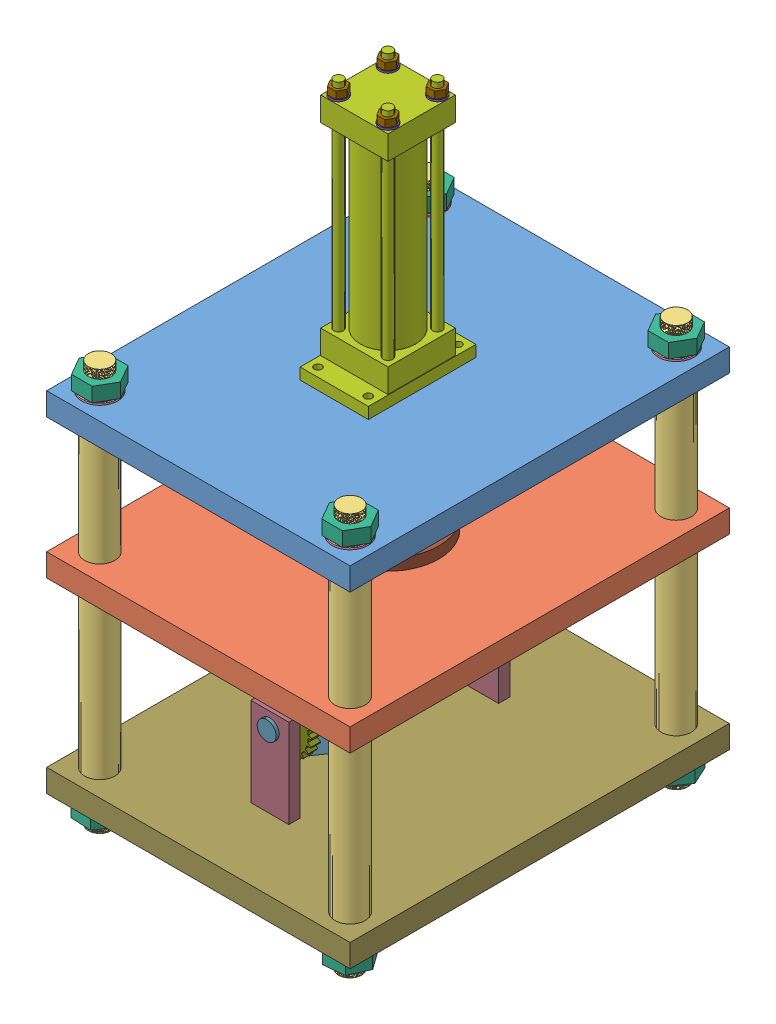
SolidWorks assembly Ensamblaje 1 placas, configuration Predeterminado. Lengths in mm.
Overall size (508 1049.7 635).
49 component instances, 16 part files, 76 mates.
Components (placement in the parent):
- placa 1-1: placa 1 [Predeterminado] at (113.4561 256.4005 589.4712) size (508 38.1 635)
- placa 2-1: placa 2 [Predeterminado] at (113.4561 22.9179 589.4712) size (508 38.1 635)
- Tarrox-1: Tarrox [Predeterminado] at (323.0061 -334.1495 862.5212) x (0.933111 0 -0.359587) z (0.359587 0 0.933111) size (50.8 673.1 50.8)
- Tarrox-2: Tarrox [Predeterminado] at (323.0061 -334.1495 316.4212) x (0.79348 0 -0.608597) z (0.608597 0 0.79348) size (50.8 673.1 50.8)
- Tarrox-3: Tarrox [Predeterminado] at (-96.0939 -334.1495 862.5212) size (50.8 673.1 50.8)
- Tarrox-4: Tarrox [Predeterminado] at (-96.0939 -334.1495 316.4212) size (50.8 673.1 50.8)
- rondana plana de 1.5in-1: rondana plana de 1.5in [Predeterminado] at (-96.0939 294.5005 862.5212) x (0.930502 0 0.366288) z (-0.366288 0 0.930502) size (60 3 60)
- rondana plana de 1.5in-2: rondana plana de 1.5in [Predeterminado] at (323.0061 294.5005 862.5212) x (0.967524 0 0.252778) z (-0.252778 0 0.967524) size (60 3 60)
- rondana plana de 1.5in-3: rondana plana de 1.5in [Predeterminado] at (323.0061 294.5005 316.4212) size (60 3 60)
- rondana plana de 1.5in-4: rondana plana de 1.5in [Predeterminado] at (-96.0939 294.5005 316.4212) x (-0.006863 0 -0.999976) z (0.999976 0 -0.006863) size (60 3 60)
- rondana plana de 1.5in-5: rondana plana de 1.5in [Predeterminado] at (-96.0939 -292.6995 862.5212) x (0.88029 0 -0.474437) z (0.474437 0 0.88029) size (60 3 60)
- rondana plana de 1.5in-6: rondana plana de 1.5in [Predeterminado] at (323.0061 -292.6995 862.5212) x (0.975439 0 0.220268) z (-0.220268 0 0.975439) size (60 3 60)
- rondana plana de 1.5in-7: rondana plana de 1.5in [Predeterminado] at (323.0061 -292.6995 316.4212) size (60 3 60)
- rondana plana de 1.5in-8: rondana plana de 1.5in [Predeterminado] at (-96.0939 -292.6995 316.4212) size (60 3 60)
- rondana de presión-1: rondana de presión [Predeterminado] at (323.0061 297.5005 862.5212) size (55 3 54.98)
- rondana de presión-2: rondana de presión [Predeterminado] at (-96.0939 297.5005 862.5212) size (55 3 54.98)
- rondana de presión-3: rondana de presión [Predeterminado] at (323.0061 297.5005 316.4212) size (55 3 54.98)
- rondana de presión-4: rondana de presión [Predeterminado] at (-96.0939 297.5005 316.4212) size (55 3 54.98)
- rondana de presión-5: rondana de presión [Predeterminado] at (-96.0939 -295.6995 862.5212) x (0.998826 0 0.048446) z (-0.048446 0 0.998826) size (55 3 54.98)
- rondana de presión-6: rondana de presión [Predeterminado] at (-96.0939 -295.6995 316.4212) x (0.996973 0 -0.077754) z (0.077754 0 0.996973) size (55 3 54.98)
- rondana de presión-7: rondana de presión [Predeterminado] at (323.0061 -295.6995 316.4212) size (55 3 54.98)
- rondana de presión-8: rondana de presión [Predeterminado] at (323.0061 -295.6995 862.5212) size (55 3 54.98)
- tuerca de 1.5in-1: tuerca de 1.5in [Predeterminado] at (323.0061 300.5005 862.5212) size (69.28 24 60)
- tuerca de 1.5in-2: tuerca de 1.5in [Predeterminado] at (-96.0939 300.5005 862.5212) size (69.28 24 60)
- tuerca de 1.5in-3: tuerca de 1.5in [Predeterminado] at (323.0061 300.5005 316.4212) size (69.28 24 60)
- tuerca de 1.5in-4: tuerca de 1.5in [Predeterminado] at (-96.0939 300.5005 316.4212) size (69.28 24 60)
- tuerca de 1.5in-5: tuerca de 1.5in [Predeterminado] at (323.0061 -319.6995 862.5212) x (-0.995095 0 0.098924) z (-0.098924 0 -0.995095) size (69.28 24 60)
- tuerca de 1.5in-6: tuerca de 1.5in [Predeterminado] at (323.0061 -319.6995 316.4212) x (-0.995824 0 -0.091299) z (0.091299 0 -0.995824) size (69.28 24 60)
- tuerca de 1.5in-7: tuerca de 1.5in [Predeterminado] at (-96.0939 -319.6995 316.4212) x (-0.401422 0 -0.915893) z (0.915893 0 -0.401422) size (69.28 24 60)
- tuerca de 1.5in-8: tuerca de 1.5in [Predeterminado] at (-96.0939 -319.6995 862.5212) x (-0.998486 0 -0.055002) z (0.055002 0 -0.998486) size (69.28 24 60)
- Ensamblaje piston-1: Ensamblaje piston [Predeterminado] at (194.8258 497.708 168.4212) size (114.3 421.05 180)
  - base de piston-1: base de piston [Predeterminado] at (-81.3698 -203.2076 421.05) size (114.3 421.05 180)
  - rondana de 16mm-1: rondana de 16mm [Predeterminado] at (-122.726 193.8424 462.4062) size (28 3 28)
  - rondana de 16mm-2: rondana de 16mm [Predeterminado] at (-122.726 193.8424 379.6938) size (28 3 28)
  - rondana de 16mm-3: rondana de 16mm [Predeterminado] at (-40.0135 193.8424 462.4062) x (0.999451 0 0.033137) z (-0.033137 0 0.999451) size (28 3 28)
  - rondana de 16mm-4: rondana de 16mm [Predeterminado] at (-40.0135 193.8424 379.6938) size (28 3 28)
  - tuerca de 16mm-1: tuerca de 16mm [Predeterminado] at (-40.0135 196.8424 462.4062) size (27.71 12 24.32)
  - tuerca de 16mm-2: tuerca de 16mm [Predeterminado] at (-40.0135 196.8424 379.6938) size (27.71 12 24.32)
  - tuerca de 16mm-3: tuerca de 16mm [Predeterminado] at (-122.726 196.8424 462.4062) size (27.71 12 24.32)
  - tuerca de 16mm-4: tuerca de 16mm [Predeterminado] at (-122.726 196.8424 379.6938) size (27.71 12 24.32)
- bastago 1-1: bastago 1 [Predeterminado] at (113.4561 101.0679 589.4712) x (0.034652 0 0.999399) z (-0.999399 0 0.034652) size (45 254 45)
- brida-1: brida [Predeterminado] at (113.4561 61.0179 589.4712) size (170 40.05 170)
- placa 3-1: placa 3 [Predeterminado] at (113.4561 -289.6995 589.4712) size (508 38.1 635)
- base de mamelon 1-1: base de mamelon 1 [Predeterminado] at (81.7061 -251.5995 768.2712) size (63.5 148.55 19.05)
- base de mamelon 1-2: base de mamelon 1 [Predeterminado] at (81.7061 -251.5995 417.0212) size (63.5 148.55 19.05)
- Ensamblaje 10-2: Ensamblaje 10 [Predeterminado] at (114.3023 -116.2053 284.6712) x (-0.012069 0.999927 0) z (0 0 1) size (127 160.79 381)
  - exagono 1-1: exagono 1 [Predeterminado] at (-12.2332 0.9939 457.2) size (127 109.99 381)
  - base 10-1: base 10 [Predeterminado] at (-43.9832 55.9866 431.8) size (63.5 50.8 254)
  - engrane 1-1: engrane 1 [Predeterminado] at (-12.2332 0.9939 466.725) x (0.999934 -0.011529 0) z (0 0 1) size (101.2 101.2 15.88)
Mates (geometry in assembly coordinates):
- Coincidente5: coincident aligned: plane of placa 1-1 through (-140.5439 294.5005 906.9712) normal (0 0 1); plane of placa 2-1 through (-140.5439 61.0179 906.9712) normal (0 0 1)
- Coincidente6: coincident aligned: plane of placa 1-1 through (367.4561 294.5005 906.9712) normal (1 0 0); plane of placa 2-1 through (367.4561 61.0179 906.9712) normal (1 0 0)
- Concéntrica1: concentric aligned: cylinder of placa 1-1 through (323.0061 202.5189 862.5212) axis (0 1 0) radius 19.05; cylinder of Tarrox-1 through (323.0061 256.4005 862.5212) axis (0 1 0) radius 19.05
- Coincidente7: coincident anti-aligned: plane of placa 1-1 through (113.4561 256.4005 589.4712) normal (0 -1 0); plane of Tarrox-1 through (323.0061 256.4005 862.5212) normal (0 1 0)
- Concéntrica2: concentric aligned: cylinder of placa 1-1 through (323.0061 202.5189 316.4212) axis (0 1 0) radius 19.05; cylinder of Tarrox-2 through (323.0061 256.4005 316.4212) axis (0 1 0) radius 19.05
- Coincidente8: coincident anti-aligned: plane of placa 1-1 through (113.4561 256.4005 589.4712) normal (0 -1 0); plane of Tarrox-2 through (323.0061 256.4005 316.4212) normal (0 1 0)
- Concéntrica3: concentric aligned: cylinder of placa 1-1 through (-96.0939 202.5189 862.5212) axis (0 1 0) radius 19.05; cylinder of Tarrox-3 through (-96.0939 256.4005 862.5212) axis (0 1 0) radius 19.05
- Coincidente9: coincident anti-aligned: plane of placa 1-1 through (113.4561 256.4005 589.4712) normal (0 -1 0); plane of Tarrox-3 through (-96.0939 256.4005 862.5212) normal (0 1 0)
- Concéntrica4: concentric aligned: cylinder of placa 1-1 through (-96.0939 202.5189 316.4212) axis (0 1 0) radius 19.05; cylinder of Tarrox-4 through (-96.0939 256.4005 316.4212) axis (0 1 0) radius 19.05
- Coincidente10: coincident anti-aligned: plane of placa 1-1 through (113.4561 256.4005 589.4712) normal (0 -1 0); plane of Tarrox-4 through (-96.0939 256.4005 316.4212) normal (0 1 0)
- Concéntrica5: concentric aligned: cylinder of Tarrox-3 through (-96.0939 338.9505 862.5212) axis (0 -1 0) radius 25.4; cylinder of rondana plana de 1.5in-1 through (-96.0939 297.5005 862.5212) axis (0 -1 0) radius 19.05
- Coincidente11: coincident anti-aligned: plane of placa 1-1 through (113.4561 294.5005 589.4712) normal (0 1 0); plane of rondana plana de 1.5in-1 through (-96.0939 294.5005 862.5212) normal (0 -1 0)
- Concéntrica6: concentric aligned: cylinder of Tarrox-1 through (323.0061 338.9505 862.5212) axis (0 -1 0) radius 25.4; cylinder of rondana plana de 1.5in-2 through (323.0061 297.5005 862.5212) axis (0 -1 0) radius 19.05
- Coincidente12: coincident anti-aligned: plane of placa 1-1 through (113.4561 294.5005 589.4712) normal (0 1 0); plane of rondana plana de 1.5in-2 through (323.0061 294.5005 862.5212) normal (0 -1 0)
- Concéntrica7: concentric aligned: cylinder of Tarrox-2 through (323.0061 338.9505 316.4212) axis (0 -1 0) radius 25.4; cylinder of rondana plana de 1.5in-3 through (323.0061 297.5005 316.4212) axis (0 -1 0) radius 19.05
- Coincidente13: coincident anti-aligned: plane of placa 1-1 through (113.4561 294.5005 589.4712) normal (0 1 0); plane of rondana plana de 1.5in-3 through (323.0061 294.5005 316.4212) normal (0 -1 0)
- Concéntrica8: concentric aligned: cylinder of Tarrox-4 through (-96.0939 338.9505 316.4212) axis (0 -1 0) radius 25.4; cylinder of rondana plana de 1.5in-4 through (-96.0939 297.5005 316.4212) axis (0 -1 0) radius 19.05
- Coincidente14: coincident anti-aligned: plane of placa 1-1 through (113.4561 294.5005 589.4712) normal (0 1 0); plane of rondana plana de 1.5in-4 through (-96.0939 294.5005 316.4212) normal (0 -1 0)
- Concéntrica9: concentric aligned: cylinder of Tarrox-3 through (-96.0939 338.9505 862.5212) axis (0 -1 0) radius 25.4; cylinder of rondana plana de 1.5in-5 through (-96.0939 -289.6995 862.5212) axis (0 -1 0) radius 19.05
- Concéntrica10: concentric aligned: cylinder of Tarrox-1 through (323.0061 338.9505 862.5212) axis (0 -1 0) radius 25.4; cylinder of rondana plana de 1.5in-6 through (323.0061 -289.6995 862.5212) axis (0 -1 0) radius 19.05
- Concéntrica11: concentric aligned: cylinder of Tarrox-2 through (323.0061 338.9505 316.4212) axis (0 -1 0) radius 25.4; cylinder of rondana plana de 1.5in-7 through (323.0061 -289.6995 316.4212) axis (0 -1 0) radius 19.05
- Concéntrica12: concentric aligned: cylinder of Tarrox-4 through (-96.0939 338.9505 316.4212) axis (0 -1 0) radius 25.4; cylinder of rondana plana de 1.5in-8 through (-96.0939 -289.6995 316.4212) axis (0 -1 0) radius 19.05
- Concéntrica13: concentric aligned: cylinder of Tarrox-1 through (323.0061 338.9505 862.5212) axis (0 -1 0) radius 25.4; cylinder of rondana de presión-1 through (323.0061 300.5005 862.5212) axis (0 -1 0) radius 19.05
- Coincidente19: coincident anti-aligned: plane of rondana plana de 1.5in-2 through (323.0061 297.5005 862.5212) normal (0 1 0); plane of rondana de presión-1 through (323.0061 297.5005 862.5212) normal (0 -1 0)
- Concéntrica14: concentric aligned: cylinder of Tarrox-3 through (-96.0939 338.9505 862.5212) axis (0 -1 0) radius 25.4; cylinder of rondana de presión-2 through (-96.0939 300.5005 862.5212) axis (0 -1 0) radius 19.05
- Coincidente20: coincident anti-aligned: plane of rondana plana de 1.5in-1 through (-96.0939 297.5005 862.5212) normal (0 1 0); plane of rondana de presión-2 through (-96.0939 297.5005 862.5212) normal (0 -1 0)
- Concéntrica15: concentric aligned: cylinder of Tarrox-2 through (323.0061 338.9505 316.4212) axis (0 -1 0) radius 25.4; cylinder of rondana de presión-3 through (323.0061 300.5005 316.4212) axis (0 -1 0) radius 19.05
- Coincidente21: coincident anti-aligned: plane of rondana plana de 1.5in-3 through (323.0061 297.5005 316.4212) normal (0 1 0); plane of rondana de presión-3 through (323.0061 297.5005 316.4212) normal (0 -1 0)
- Concéntrica16: concentric aligned: cylinder of Tarrox-4 through (-96.0939 338.9505 316.4212) axis (0 -1 0) radius 25.4; cylinder of rondana de presión-4 through (-96.0939 300.5005 316.4212) axis (0 -1 0) radius 19.05
- Coincidente22: coincident anti-aligned: plane of rondana plana de 1.5in-4 through (-96.0939 297.5005 316.4212) normal (0 1 0); plane of rondana de presión-4 through (-96.0939 297.5005 316.4212) normal (0 -1 0)
- Concéntrica17: concentric aligned: cylinder of Tarrox-3 through (-96.0939 338.9505 862.5212) axis (0 -1 0) radius 25.4; cylinder of rondana de presión-5 through (-96.0939 -292.6995 862.5212) axis (0 -1 0) radius 19.05
- Coincidente23: coincident anti-aligned: plane of rondana plana de 1.5in-5 through (-96.0939 -292.6995 862.5212) normal (0 -1 0); plane of rondana de presión-5 through (-96.0939 -292.6995 862.5212) normal (0 1 0)
- Concéntrica18: concentric aligned: cylinder of Tarrox-4 through (-96.0939 338.9505 316.4212) axis (0 -1 0) radius 25.4; cylinder of rondana de presión-6 through (-96.0939 -292.6995 316.4212) axis (0 -1 0) radius 19.05
- Coincidente24: coincident anti-aligned: plane of rondana plana de 1.5in-8 through (-96.0939 -292.6995 316.4212) normal (0 -1 0); plane of rondana de presión-6 through (-96.0939 -292.6995 316.4212) normal (0 1 0)
- Coincidente25: coincident anti-aligned: plane of rondana plana de 1.5in-7 through (323.0061 -292.6995 316.4212) normal (0 -1 0); plane of rondana de presión-7 through (323.0061 -292.6995 316.4212) normal (0 1 0)
- Concéntrica19: concentric aligned: cylinder of Tarrox-2 through (323.0061 338.9505 316.4212) axis (0 -1 0) radius 25.4; cylinder of rondana de presión-7 through (323.0061 -292.6995 316.4212) axis (0 -1 0) radius 19.05
- Coincidente26: coincident anti-aligned: plane of rondana plana de 1.5in-6 through (323.0061 -292.6995 862.5212) normal (0 -1 0); plane of rondana de presión-8 through (323.0061 -292.6995 862.5212) normal (0 1 0)
- Concéntrica20: concentric aligned: cylinder of Tarrox-1 through (323.0061 338.9505 862.5212) axis (0 -1 0) radius 25.4; cylinder of rondana de presión-8 through (323.0061 -292.6995 862.5212) axis (0 -1 0) radius 19.05
- Concéntrica21: concentric aligned: cylinder of Tarrox-1 through (323.0061 338.9505 862.5212) axis (0 -1 0) radius 25.4; cylinder of tuerca de 1.5in-1 through (323.0061 324.5005 862.5212) axis (0 -1 0) radius 19.05
- Coincidente27: coincident anti-aligned: plane of rondana de presión-1 through (323.0061 300.5005 862.5212) normal (0 1 0); plane of tuerca de 1.5in-1 through (323.0061 300.5005 862.5212) normal (0 -1 0)
- Concéntrica22: concentric aligned: cylinder of Tarrox-3 through (-96.0939 338.9505 862.5212) axis (0 -1 0) radius 25.4; cylinder of tuerca de 1.5in-2 through (-96.0939 324.5005 862.5212) axis (0 -1 0) radius 19.05
- Coincidente28: coincident anti-aligned: plane of rondana de presión-2 through (-96.0939 300.5005 862.5212) normal (0 1 0); plane of tuerca de 1.5in-2 through (-96.0939 300.5005 862.5212) normal (0 -1 0)
- Concéntrica23: concentric aligned: cylinder of Tarrox-2 through (323.0061 338.9505 316.4212) axis (0 -1 0) radius 25.4; cylinder of tuerca de 1.5in-3 through (323.0061 324.5005 316.4212) axis (0 -1 0) radius 19.05
- Coincidente29: coincident anti-aligned: plane of rondana de presión-3 through (323.0061 300.5005 316.4212) normal (0 1 0); plane of tuerca de 1.5in-3 through (323.0061 300.5005 316.4212) normal (0 -1 0)
- Coincidente30: coincident anti-aligned: plane of rondana de presión-4 through (-96.0939 300.5005 316.4212) normal (0 1 0); plane of tuerca de 1.5in-4 through (-96.0939 300.5005 316.4212) normal (0 -1 0)
- Concéntrica24: concentric aligned: cylinder of Tarrox-4 through (-96.0939 338.9505 316.4212) axis (0 -1 0) radius 25.4; cylinder of tuerca de 1.5in-4 through (-96.0939 324.5005 316.4212) axis (0 -1 0) radius 19.05
- Coincidente31: coincident anti-aligned: plane of rondana de presión-8 through (323.0061 -295.6995 862.5212) normal (0 -1 0); plane of tuerca de 1.5in-5 through (323.0061 -295.6995 862.5212) normal (0 1 0)
- Concéntrica25: concentric aligned: cylinder of Tarrox-1 through (323.0061 338.9505 862.5212) axis (0 -1 0) radius 25.4; cylinder of tuerca de 1.5in-5 through (323.0061 -295.6995 862.5212) axis (0 -1 0) radius 19.05
- Concéntrica26: concentric aligned: cylinder of Tarrox-2 through (323.0061 338.9505 316.4212) axis (0 -1 0) radius 25.4; cylinder of tuerca de 1.5in-6 through (323.0061 -295.6995 316.4212) axis (0 -1 0) radius 19.05
- Coincidente32: coincident anti-aligned: plane of rondana de presión-7 through (323.0061 -295.6995 316.4212) normal (0 -1 0); plane of tuerca de 1.5in-6 through (323.0061 -295.6995 316.4212) normal (0 1 0)
- Concéntrica27: concentric aligned: cylinder of Tarrox-4 through (-96.0939 338.9505 316.4212) axis (0 -1 0) radius 25.4; cylinder of tuerca de 1.5in-7 through (-96.0939 -295.6995 316.4212) axis (0 -1 0) radius 19.05
- Coincidente33: coincident anti-aligned: plane of rondana de presión-6 through (-96.0939 -295.6995 316.4212) normal (0 -1 0); plane of tuerca de 1.5in-7 through (-96.0939 -295.6995 316.4212) normal (0 1 0)
- Concéntrica28: concentric aligned: cylinder of Tarrox-3 through (-96.0939 338.9505 862.5212) axis (0 -1 0) radius 25.4; cylinder of tuerca de 1.5in-8 through (-96.0939 -295.6995 862.5212) axis (0 -1 0) radius 19.05
- Coincidente34: coincident anti-aligned: plane of rondana de presión-5 through (-96.0939 -295.6995 862.5212) normal (0 -1 0); plane of tuerca de 1.5in-8 through (-96.0939 -295.6995 862.5212) normal (0 1 0)
- Ancho3: width aligned: plane of placa 1-1 through (-140.5439 294.5005 906.9712) normal (0 0 1); plane of placa 1-1 through (-140.5439 294.5005 271.9712) normal (0 0 -1); plane of Ensamblaje piston-1/base de piston-1 through (56.3061 313.5505 679.4712) normal (0 0 1); plane of Ensamblaje piston-1/base de piston-1 through (56.3061 313.5505 499.4712) normal (0 0 -1)
- Coincidente35: coincident anti-aligned: plane of placa 1-1 through (113.4561 294.5005 589.4712) normal (0 1 0); plane of Ensamblaje piston-1/base de piston-1 through (113.4561 294.5005 589.4712) normal (0 -1 0)
- Ancho4: width aligned: plane of placa 1-1 through (367.4561 294.5005 906.9712) normal (1 0 0); plane of placa 1-1 through (-140.5439 294.5005 906.9712) normal (-1 0 0); plane of Ensamblaje piston-1/base de piston-1 through (170.6061 313.5505 679.4712) normal (1 0 0); plane of Ensamblaje piston-1/base de piston-1 through (56.3061 313.5505 679.4712) normal (-1 0 0)
- Concéntrica29: concentric anti-aligned: cylinder of placa 1-1 through (113.4561 192.7609 589.4712) axis (0 1 0) radius 22.5; cylinder of bastago 1-1 through (113.4561 355.0679 589.4712) axis (0 -1 0) radius 22.5
- Concéntrica30: concentric aligned: cylinder of bastago 1-1 through (113.4561 355.0679 589.4712) axis (0 -1 0) radius 22.5; cylinder of brida-1 through (113.4561 101.0679 589.4712) axis (0 -1 0) radius 31.75
- Coincidente36: coincident anti-aligned: plane of placa 2-1 through (113.4561 61.0179 589.4712) normal (0 1 0); plane of brida-1 through (113.4561 61.0179 589.4712) normal (0 -1 0)
- Coincidente37: coincident anti-aligned: plane of bastago 1-1 through (113.4561 101.0679 589.4712) normal (0 -1 0); plane of brida-1 through (113.4561 101.0679 589.4712) normal (0 1 0)
- Concéntrica31: concentric anti-aligned: cylinder of Tarrox-3 through (-96.0939 -251.5995 862.5212) axis (0 -1 0) radius 19.05; cylinder of placa 3-1 through (-96.0939 -343.5811 862.5212) axis (0 1 0) radius 19.05
- Concéntrica32: concentric anti-aligned: cylinder of Tarrox-2 through (323.0061 -251.5995 316.4212) axis (0 -1 0) radius 19.05; cylinder of placa 3-1 through (323.0061 -343.5811 316.4212) axis (0 1 0) radius 19.05
- Coincidente38: coincident anti-aligned: plane of Tarrox-2 through (323.0061 -251.5995 316.4212) normal (0 -1 0); plane of placa 3-1 through (113.4561 -251.5995 589.4712) normal (0 1 0)
- Coincidente39: coincident anti-aligned: plane of rondana plana de 1.5in-7 through (323.0061 -289.6995 316.4212) normal (0 1 0); plane of placa 3-1 through (113.4561 -289.6995 589.4712) normal (0 -1 0)
- Coincidente40: coincident anti-aligned: plane of rondana plana de 1.5in-8 through (-96.0939 -289.6995 316.4212) normal (0 1 0); plane of placa 3-1 through (113.4561 -289.6995 589.4712) normal (0 -1 0)
- Coincidente41: coincident anti-aligned: plane of rondana plana de 1.5in-6 through (323.0061 -289.6995 862.5212) normal (0 1 0); plane of placa 3-1 through (113.4561 -289.6995 589.4712) normal (0 -1 0)
- Coincidente42: coincident anti-aligned: plane of rondana plana de 1.5in-5 through (-96.0939 -289.6995 862.5212) normal (0 1 0); plane of placa 3-1 through (113.4561 -289.6995 589.4712) normal (0 -1 0)
- Coincidente43: coincident anti-aligned: plane of placa 3-1 through (113.4561 -251.5995 589.4712) normal (0 1 0); plane of base de mamelon 1-1 through (81.7061 -251.5995 787.3212) normal (0 -1 0)
- Ancho7: width aligned: plane of placa 3-1 through (-140.5439 -251.5995 906.9712) normal (-1 0 0); plane of placa 3-1 through (367.4561 -251.5995 906.9712) normal (1 0 0); plane of base de mamelon 1-1 through (81.7061 -251.5995 787.3212) normal (-1 0 0); plane of base de mamelon 1-1 through (145.2061 -251.5995 787.3212) normal (1 0 0)
- Coincidente45: coincident anti-aligned: plane of placa 3-1 through (113.4561 -251.5995 589.4712) normal (0 1 0); plane of base de mamelon 1-2 through (81.7061 -251.5995 436.0712) normal (0 -1 0)
- Ancho8: width aligned: plane of placa 3-1 through (-140.5439 -251.5995 906.9712) normal (-1 0 0); plane of placa 3-1 through (367.4561 -251.5995 906.9712) normal (1 0 0); plane of base de mamelon 1-2 through (81.7061 -251.5995 436.0712) normal (-1 0 0); plane of base de mamelon 1-2 through (145.2061 -251.5995 436.0712) normal (1 0 0)
- Distancia3: distance = 119.65 mm aligned: plane of base de mamelon 1-1 through (81.7061 -251.5995 787.3212) normal (0 0 1); plane of placa 3-1 through (-140.5439 -251.5995 906.9712) normal (0 0 1)
- Distancia4: distance = 145.05 mm aligned: plane of base de mamelon 1-2 through (81.7061 -251.5995 417.0212) normal (0 0 -1); plane of placa 3-1 through (-140.5439 -251.5995 271.9712) normal (0 0 -1)
- Concéntrica34: concentric anti-aligned: cylinder of base de mamelon 1-1 through (113.4561 -128.4495 768.2712) axis (0 0 1) radius 15.875; cylinder of Ensamblaje 10-2/exagono 1-1 through (113.4561 -128.4495 792.6712) axis (0 0 -1) radius 15.875
- Distancia5: distance = 1 mm anti-aligned: plane of Ensamblaje 10-2/engrane 1-1 through (113.4561 -128.4495 767.2712) normal (0 0 1); plane of base de mamelon 1-1 through (81.7061 -251.5995 768.2712) normal (0 0 -1)
